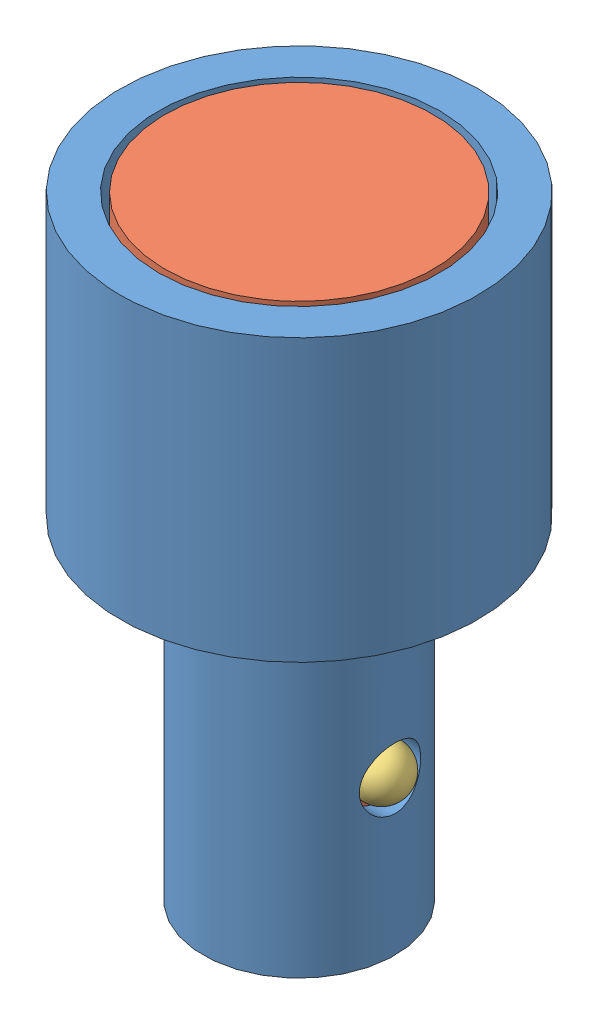
SolidWorks assembly Thesis0_assy, configuration Default. Lengths in mm.
Overall size (46.85 79.5 46.85).
6 component instances, 5 part files, 11 mates.
Components (placement in the parent):
- Thesis1_housing-1: Thesis1_housing [Default] at (16.5285 68.7578 58.7233) size (44.45 76.2 44.45)
- Thesis1_plunger-1: Thesis1_plunger [Default] at (16.5285 30.6578 58.7233) x (0.781264 0 -0.6242) z (0.6242 0 0.781264) size (33.34 66.67 33.34)
- ball_bearing_.25-1: ball_bearing_.25 [Default] at (6.2802 40.1828 58.7233) x (0.527415 -0.838476 0.137083) z (-0.844798 -0.534702 -0.020252) size (6.35 6.35 6.35)
- ball_bearing_.25-2: ball_bearing_.25 [Default] at (26.7768 40.1828 58.7233) x (-0.89186 0.448616 0.0577) z (-0.404038 -0.847511 0.344207) size (6.35 6.35 6.35)
- 9657K528_COMPRESSION SPRING-1: 9657K528_COMPRESSION SPRING [9657K528] at (16.5285 100.5078 58.7233) x (1 0 0) z (0 1 0) size (32.07 31.82 31.87)
- 9434K154_MUSIC-WIRE STEEL COMPRESSION SPRINGS-1: 9434K154_MUSIC-WIRE STEEL COMPRESSION SPRINGS [9434K154] at (16.5285 11.6078 58.7233) x (0.781264 0 -0.6242) z (0.6242 0 0.781264) size (19.21 8.89 18.74)
Mates (geometry in assembly coordinates):
- Concentric1: concentric: cylinder of Thesis1_housing-1 through (16.5285 97.3328 58.7233) axis (0 -1 0) radius 17.4625; cylinder of Thesis1_plunger-1 through (16.5285 97.3328 58.7233) axis (0 -1 0) radius 16.6687
- Concentric3: concentric: cylinder of Thesis1_housing-1 through (38.7535 40.1828 58.7233) axis (-1 0 0) radius 3.81; sphere of ball_bearing_.25-2
- Concentric4: concentric: cylinder of Thesis1_housing-1 through (-5.6965 40.1828 58.7233) axis (1 0 0) radius 3.81; sphere of ball_bearing_.25-1
- Tangent9: tangent: cone of Thesis1_plunger-1 through (16.5285 42.2537 58.7233) axis (0 1 0); sphere of ball_bearing_.25-2
- Tangent10: tangent: cone of Thesis1_plunger-1 through (16.5285 42.2537 58.7233) axis (0 1 0); sphere of ball_bearing_.25-1
- Coincident3: coincident: plane of Thesis1_housing-1 through (16.5285 68.7578 58.7233) normal (0 1 0); plane of 9657K528_COMPRESSION SPRING-1 through (16.5285 68.7578 58.7233) normal (0 -1 0)
- Concentric5: concentric: cylinder of Thesis1_plunger-1 through (16.5285 97.3328 58.7233) axis (0 -1 0) radius 16.6687; line of 9657K528_COMPRESSION SPRING-1 through (16.5285 100.5078 58.7233) axis (0 1 0)
- Distance2: distance = 0 mm: plane of Thesis1_housing-1 through (16.5285 97.3328 58.7233) normal (0 1 0); plane of Thesis1_plunger-1 through (16.5285 97.3328 58.7233) normal (0 1 0)
- Coincident4: coincident: plane of Thesis1_plunger-1 through (16.5285 30.6578 58.7233) normal (0 -1 0); plane of 9434K154_MUSIC-WIRE STEEL COMPRESSION SPRINGS-1 through (3.6769 30.6578 57.287) normal (0 1 0)
- Coincident5: coincident: plane of Thesis1_plunger-1 through (16.5285 30.6578 58.7233) normal (0.6242 0 0.781264); plane of 9434K154_MUSIC-WIRE STEEL COMPRESSION SPRINGS-1 through (16.5285 11.6078 58.7233) normal (0.6242 0 0.781264)
- Coincident6: coincident: plane of Thesis1_plunger-1 through (16.5285 30.6578 58.7233) normal (0.781264 0 -0.6242); plane of 9434K154_MUSIC-WIRE STEEL COMPRESSION SPRINGS-1 through (16.5285 11.6078 58.7233) normal (0.781264 0 -0.6242)
